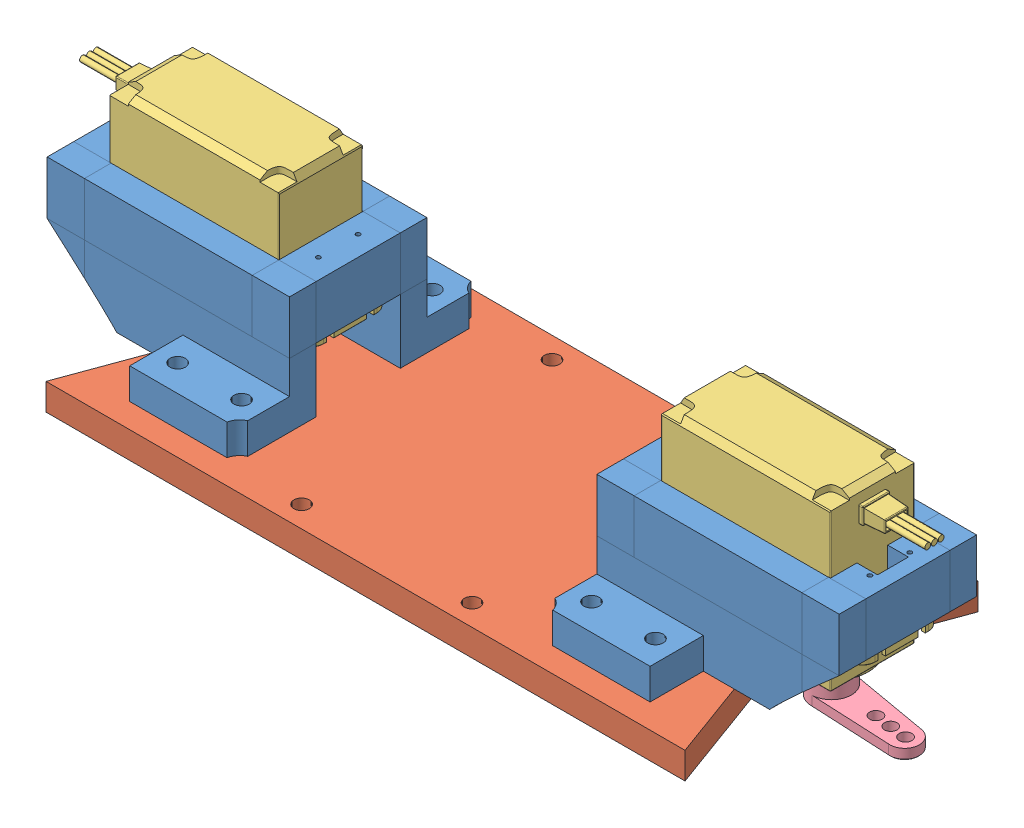
SolidWorks assembly shoulders update, configuration Default. Lengths in mm.
Overall size (201.45 49.61 69.85).
7 component instances, 4 part files, 16 mates.
Components (placement in the parent):
- servomount v1-1: servomount v1 [Default] at (-53.4665 54.2419 -24.7514) size (57.78 27.96 58.16)
- servo mount plate hips V1-1: servo mount plate hips V1 [Default] at (-18.1341 79.1339 42.9263) size (152.35 6.35 69.85)
- sunfounder_20kgSLDPRT-1: sunfounder_20kgSLDPRT [Default] at (9.2572 109.3419 -14.7814) x (0 0 -1) z (-1 0 0) size (20 46.03 62.2)
- 25T Servo Horn Steering Arm M3-1: 25T Servo Horn Steering Arm M3 [Default] at (19.7072 81.8141 -24.7814) x (0.111235 0 -0.993794) z (0 1 0) size (9.5 28 7.5)
- servomount v1-2: servomount v1 [Default] at (-59.4691 54.2419 -24.7514) x (-1 0 0) z (0 0 -1) size (57.78 27.96 58.16)
- sunfounder_20kgSLDPRT-2: sunfounder_20kgSLDPRT [Default] at (-122.1928 109.3419 -34.7214) x (0 0 1) z (1 0 0) size (20 46.03 62.2)
- 25T Servo Horn Steering Arm M3-2: 25T Servo Horn Steering Arm M3 [Default] at (-132.6428 81.8141 -24.7214) x (-0.001579 0 0.999999) z (0 1 0) size (9.5 28 7.5)
Mates (geometry in assembly coordinates):
- Coincident3: coincident anti-aligned: plane of servomount v1-1 through (37.9473 100.7419 -34.7814) normal (0 -1 0); plane of sunfounder_20kgSLDPRT-1 through (-17.9428 100.7419 -15.4314) normal (0 1 0)
- Coincident4: coincident anti-aligned: plane of servomount v1-1 through (-10.9428 0.5209 -34.7814) normal (1 0 0); plane of sunfounder_20kgSLDPRT-1 through (-10.9428 109.3419 -34.7814) normal (-1 0 0)
- Coincident5: coincident anti-aligned: plane of servomount v1-1 through (-10.9428 0.5209 -34.7814) normal (0 0 1); plane of sunfounder_20kgSLDPRT-1 through (9.2572 109.3419 -34.7814) normal (0 0 -1)
- Coincident19: coincident anti-aligned: plane of servomount v1-2 through (-150.8828 100.7419 -14.7214) normal (0 -1 0); plane of sunfounder_20kgSLDPRT-2 through (-94.9928 100.7419 -34.0714) normal (0 1 0)
- Coincident20: coincident anti-aligned: plane of servomount v1-2 through (-101.9928 0.5209 -14.7214) normal (0 0 -1); plane of sunfounder_20kgSLDPRT-2 through (-122.1928 109.3419 -14.7214) normal (0 0 1)
- Coincident21: coincident anti-aligned: plane of servomount v1-2 through (-101.9928 0.5209 -14.7214) normal (-1 0 0); plane of sunfounder_20kgSLDPRT-2 through (-101.9928 109.3419 -14.7214) normal (1 0 0)
- Coincident22: coincident anti-aligned: plane of servo mount plate hips V1-1 through (-18.1341 85.4839 42.9263) normal (0 1 0); plane of servomount v1-2 through (-93.1028 85.4839 -95.5908) normal (0 -1 0)
- Coincident23: coincident aligned: plane of servomount v1-1 through (-53.4665 54.2419 4.3286) normal (0 0 1); plane of servomount v1-2 through (-59.4691 54.2419 4.3286) normal (0 0 1)
- Concentric4: concentric aligned: circle of sunfounder_20kgSLDPRT-1; circle of 25T Servo Horn Steering Arm M3-1
- Coincident25: coincident anti-aligned: plane of servomount v1-1 through (-19.8328 85.4839 46.0881) normal (0 -1 0); plane of servo mount plate hips V1-1 through (-18.1341 85.4839 42.9263) normal (0 1 0)
- Coincident30: coincident anti-aligned: plane of sunfounder_20kgSLDPRT-2 through (-122.1928 86.8141 -34.7214) normal (0 -1 0); plane of 25T Servo Horn Steering Arm M3-2 through (-132.6428 86.8141 -24.7214) normal (0 1 0)
- Concentric12: concentric anti-aligned: circle of sunfounder_20kgSLDPRT-2; circle of 25T Servo Horn Steering Arm M3-2
- Parallel1: parallel aligned: plane of servomount v1-1 through (-53.4665 54.2419 -53.8314) normal (0 0 -1); plane of servo mount plate hips V1-1 through (-56.4678 85.4839 -59.7064) normal (0 0 -1)
- Concentric16: concentric anti-aligned: circle of servo mount plate hips V1-1; circle of servomount v1-2
- Concentric17: concentric anti-aligned: cylinder of servomount v1-1; cylinder of servo mount plate hips V1-1 through (0.4872 85.4839 -2.0214) axis (0 -1 0) radius 1.27
- Coincident32: coincident anti-aligned: plane of sunfounder_20kgSLDPRT-1 through (9.2572 86.8141 -14.7814) normal (0 -1 0); plane of 25T Servo Horn Steering Arm M3-1 through (19.7072 86.8141 -24.7814) normal (0 1 0)
